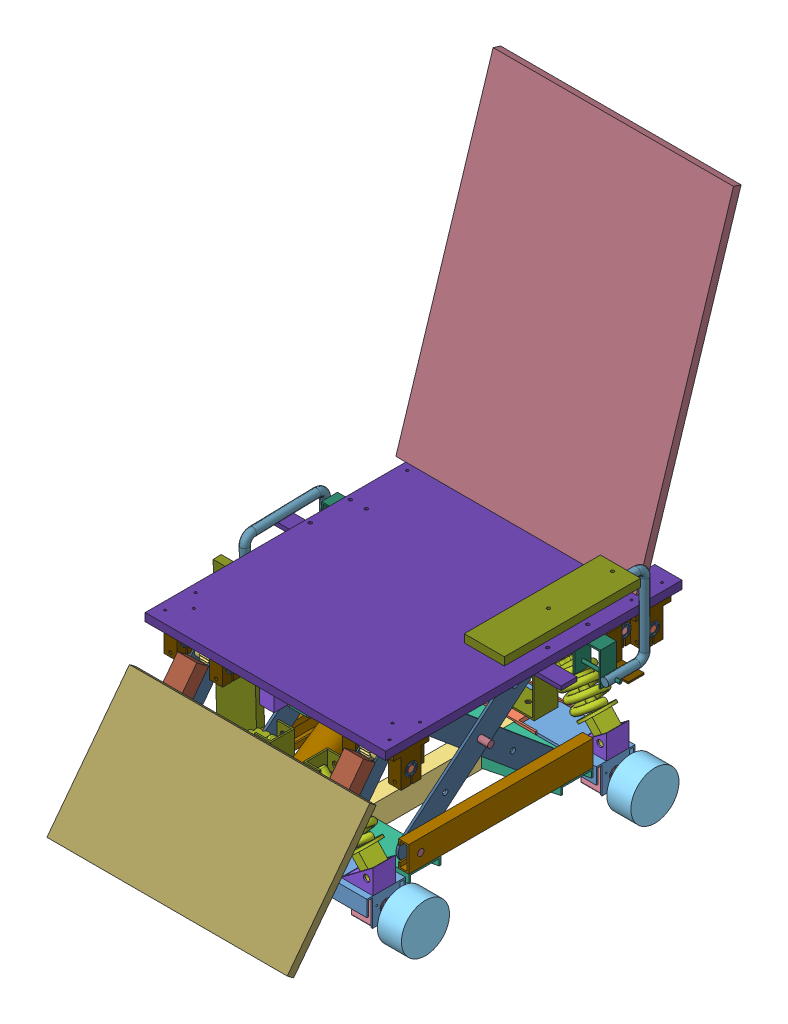
SolidWorks assembly 下半部, configuration 默认. Lengths in mm.
Overall size (394.98 643.7 566.47).
137 component instances, 36 part files, 107 mates.
Components (placement in the parent):
- 电机安装板-1: 电机安装板 [默认] at (86.7266 -11.8451 70) size (94 35 48)
- 电机转动副-1: 电机转动副 [默认] at (82.9126 -31.7003 67.7925) size (70 22 52)
- 矩管-1: 矩管 [默认] at (70.1397 -10.4653 43.5249) x (0 0 -1) z (0 1 0) size (338 20 30)
- 电机和减速器-1: 电机和减速器 [默认] at (33.1161 1.0347 94) x (0 0 1) z (-1 0 0) size (33 33 95)
- 轮子加法兰-1: 轮子加法兰 [默认] at (-93.8839 -6.7848 84.7644) x (0 0.763194 -0.646169) z (1 0 0) size (60 60 47)
- 升降支撑板-1: 升降支撑板 [默认] at (17.4717 0.0393 25.7925) size (99 30 40)
- 减震器10cm中心距-1: 减震器10cm中心距 [默认] at (-6.3734 50.215 84.5) x (0.68369 0.729773 0) z (0 0 1) size (112 51.88 51.88)
- 减震器安装支架-1: 减震器安装支架 [默认] at (-18.6767 23.9575 82.5) size (40 30 28)
- 导轨-1: 导轨 [默认] at (-3.9885 11.2083 65.7925) x (-1 0 0) z (0 0 -1) size (13 32 230)
- 升降剪叉机构-1: 升降剪叉机构 [默认] at (-28.8839 71.3664 -103.1847) x (0 0.642238 0.766505) z (1 0 0) size (258 30 3)
- 轴承带丝杆-1: 轴承带丝杆 [默认] at (-42.8839 24.6479 -118.7691) x (0 -0.824839 -0.565367) z (1 0 0) size (28 28 21)
- 升降剪叉机构-3: 升降剪叉机构 [默认] at (-31.8839 50.9021 12.8599) x (0 0.642238 -0.766505) z (1 0 0) size (258 30 3)
- 轴承带丝杆-2: 轴承带丝杆 [默认] at (-42.8839 173.169 -132.4789) x (0 0.15708 -0.987586) z (1 0 0) size (28 28 21)
- 减震器10cm中心距-2: 减震器10cm中心距 [默认] at (134.6055 50.215 108.5) x (-0.68369 0.729773 0) z (0 0 -1) size (112 51.88 51.88)
- 电机安装板-2: 电机安装板 [默认] at (41.5056 -11.8451 118) x (-1 0 0) z (0 0 -1) size (94 35 48)
- 减震器安装支架-2: 减震器安装支架 [默认] at (146.9089 23.9575 110.5) x (-1 0 0) z (0 0 -1) size (40 30 28)
- 轮子加法兰-2: 轮子加法兰 [默认] at (222.1161 -6.7848 84.7644) x (0 -0.763194 0.646169) z (-1 0 0) size (60 60 47)
- 电机和减速器-2: 电机和减速器 [默认] at (95.1161 1.0347 94) x (0 0 -1) z (1 0 0) size (33 33 95)
- 升降支撑板-2: 升降支撑板 [默认] at (110.7605 0.0393 65.7925) x (-1 0 0) z (0 0 -1) size (99 30 40)
- 升降剪叉机构-6: 升降剪叉机构 [默认] at (157.1161 50.9021 -86.038) x (0 0.642238 0.766505) z (-1 0 0) size (258 30 3)
- 升降剪叉机构-7: 升降剪叉机构 [默认] at (160.1161 71.3664 30.0065) x (0 0.642238 -0.766505) z (-1 0 0) size (258 30 3)
- 轴承带丝杆-5: 轴承带丝杆 [默认] at (171.1161 35.9711 -111.0078) x (0 0.824839 0.565367) z (-1 0 0) size (28 28 21)
- 导轨-7: 导轨 [默认] at (132.2207 61.8611 65.7925) x (1 0 0) z (0 0 -1) size (13 32 230)
- 导轨-8: 导轨 [默认] at (-3.9885 157.6386 65.7925) x (-1 0 0) z (0 0 -1) size (13 32 230)
- 轴承带丝杆-6: 轴承带丝杆 [默认] at (171.1161 171.0127 -118.9215) x (0 -0.15708 0.987586) z (-1 0 0) size (28 28 21)
- 导轨-11: 导轨 [默认] at (132.2207 208.2914 65.7925) x (1 0 0) z (0 0 -1) size (13 32 230)
- 轮子加法兰-3: 轮子加法兰 [默认] at (-93.8839 -6.7848 -183.1793) x (0 -0.763194 -0.646169) z (1 0 0) size (60 60 47)
- 减震器10cm中心距-3: 减震器10cm中心距 [默认] at (-6.3734 50.215 -206.9149) x (0.68369 0.729773 0) z (0 0 1) size (112 51.88 51.88)
- 电机安装板-3: 电机安装板 [默认] at (86.7266 -11.8451 -216.4149) size (94 35 48)
- 电机和减速器-3: 电机和减速器 [默认] at (33.1161 1.0347 -192.4149) x (0 0 1) z (-1 0 0) size (33 33 95)
- 减震器安装支架-3: 减震器安装支架 [默认] at (-18.6767 23.9575 -208.9149) size (40 30 28)
- 电机安装板-4: 电机安装板 [默认] at (41.5056 -11.8451 -168.4149) x (-1 0 0) z (0 0 -1) size (94 35 48)
- 减震器10cm中心距-4: 减震器10cm中心距 [默认] at (134.6055 50.215 -182.9149) x (-0.68369 0.729773 0) z (0 0 -1) size (112 51.88 51.88)
- 减震器安装支架-4: 减震器安装支架 [默认] at (146.9089 23.9575 -180.9149) x (-1 0 0) z (0 0 -1) size (40 30 28)
- 电机和减速器-4: 电机和减速器 [默认] at (95.1161 1.0347 -192.4149) x (0 0 -1) z (1 0 0) size (33 33 95)
- 轮子加法兰-4: 轮子加法兰 [默认] at (222.1161 -6.7848 -183.1793) x (0 0.763194 0.646169) z (-1 0 0) size (60 60 47)
- 电机转动副-2: 电机转动副 [默认] at (45.3195 -31.7003 -166.2075) x (-1 0 0) z (0 0 -1) size (70 22 52)
- 升降支撑板-3: 升降支撑板 [默认] at (17.4717 0.0393 -164.2075) size (99 30 40)
- 升降支撑板-4: 升降支撑板 [默认] at (110.7605 0.0393 -124.2075) x (-1 0 0) z (0 0 -1) size (99 30 40)
- M8 25-1: M8 25 [默认] at (-19.8839 182.965 50.7925) x (0 -0.872194 0.48916) z (-1 0 0) size (8 8 25)
- M820-1: M820 [默认] at (-24.8839 109.7499 -36.5891) x (0 0.001516 0.999999) z (-1 0 0) size (8 8 20)
- M820-2: M820 [默认] at (-24.8839 36.5347 50.7925) x (0 -0.155534 0.987831) z (-1 0 0) size (8 8 20)
- M820-3: M820 [默认] at (173.1161 36.5347 50.7925) x (0 -0.155534 0.987831) z (-1 0 0) size (8 8 20)
- M8 25-2: M8 25 [默认] at (173.1161 182.965 50.7925) x (0 -0.872194 0.48916) z (-1 0 0) size (8 8 25)
- M820-4: M820 [默认] at (173.1161 109.7499 -36.5891) x (0 0.001516 0.999999) z (-1 0 0) size (8 8 20)
- 推杆安装支架-1: 推杆安装支架 [默认] at (43.6161 55.5451 52.5195) x (0 0 -1) z (1 0 0) size (31 34.5 41)
- 推杆头-1: 推杆头 [默认] at (64.4401 95.7826 -5.2303) x (1 0 0) z (0 0.829277 0.558838) size (20 100 20)
- 减震器安装架-3: 减震器安装架 [默认] at (50.8491 12.0691 -177.2075) x (0 0 -1) z (1 0 0) size (30 98.12 81)
- 减震器安装架-4: 减震器安装架 [默认] at (77.383 12.0691 78.7925) x (0 0 1) z (-1 0 0) size (30 98.12 81)
- 装配体1-1: 装配体1 [默认] at (53.789 573.965 -39.11) x (-1 0 0) z (0 -1 0) size (300 370 54)
  - 坐垫-1: 坐垫 [默认] at (-124.3252 -195.4572 365) size (300 370 10)
  - 光轴支架-1: 光轴支架 [默认] at (-142.3271 -143.8242 371.8767) x (0 -1 0) z (-1 0 0) size (44 44 16)
  - deep groove ball bearings gb-1: deep groove ball bearings gb [Rolling bearings 618-8 GB 276-94] at (-145.2035 -140.9025 402) x (-1 0 0) z (0 -0.927196 -0.374576) size (4 16 16)
  - am8-1: am8 [默认] at (-86.5971 -156.6197 405.6451) x (0 -0.279688 0.960091) z (-1 0 0) size (8 8 71.73)
  - spur gear_gb-1: spur gear_gb [GB - Spur gear 1M 20T 20PA 12FW ---S20B75H20L8.0N] at (-116.3271 -140.9025 402) x (1 0 0) z (0 0.809131 -0.587628) size (20 21.8 21.8)
  - 光轴支架-2: 光轴支架 [默认] at (-142.3271 -118.2309 371.8767) x (0 1 0) z (1 0 0) size (44 44 16)
  - deep groove ball bearings gb-2: deep groove ball bearings gb [Rolling bearings 618-8 GB 276-94] at (-129.0651 -121.1525 402) size (4 16 16)
  - M8光轴连接齿轮-1: M8光轴连接齿轮 [默认] at (-142.3271 -136.3515 404.7888) x (0 0 -1) z (1 0 0) size (8 8 104.25)
  - deep groove ball bearings gb-3: deep groove ball bearings gb [Rolling bearings 618-8 GB 276-94] at (-140.8939 -121.1525 402) size (4 16 16)
  - deep groove ball bearings gb-4: deep groove ball bearings gb [Rolling bearings 618-8 GB 276-94] at (-156.497 -140.9025 402) x (-1 0 0) z (0 -0.924225 -0.381849) size (4 16 16)
  - 联轴器-1: 联轴器 [默认] at (-26.0771 -121.1525 402) x (0 0.642544 -0.766249) z (-1 0 0) size (14 14 20)
  - 双输出涡轮蜗杆电机-1: 双输出涡轮蜗杆电机 [默认] at (-27.3331 -113.7996 418) x (0 1 0) z (0 0 -1) size (76.8 52.5 32)
  - 零件1-1: 零件1 [默认] at (-21.0771 -118.3588 384) x (0 -1 0) z (-1 0 0) size (46 34 32)
  - spur gear_gb-5: spur gear_gb [GB - Spur gear 1M 20T 20PA 12FW ---S20B75H20L8.0N] at (-116.3271 -121.1525 402) x (1 0 0) z (0 -0.733673 0.679503) size (20 21.8 21.8)
  - 光轴支架-3: 光轴支架 [默认] at (-85.2921 -143.8242 371.8767) x (0 -1 0) z (-1 0 0) size (44 44 16)
  - deep groove ball bearings gb-7: deep groove ball bearings gb [Rolling bearings 618-8 GB 276-94] at (-87.2921 -140.9025 402) x (-1 0 0) z (0 -0.924225 -0.381849) size (4 16 16)
  - deep groove ball bearings gb-8: deep groove ball bearings gb [Rolling bearings 618-8 GB 276-94] at (-99.2921 -140.9025 402) size (4 16 16)
  - 光轴支架-4: 光轴支架 [默认] at (137.6729 -143.8242 371.8767) x (0 -1 0) z (-1 0 0) size (44 44 16)
  - deep groove ball bearings gb-9: deep groove ball bearings gb [Rolling bearings 618-8 GB 276-94] at (124.5493 -140.9025 402) x (1 0 0) z (0 0.927196 0.374576) size (4 16 16)
  - deep groove ball bearings gb-10: deep groove ball bearings gb [Rolling bearings 618-8 GB 276-94] at (120.2398 -121.1525 402) x (-1 0 0) z (0 0 -1) size (4 16 16)
  - am8-2: am8 [默认] at (137.6729 -156.6197 405.6451) x (0 -0.279688 0.960091) z (-1 0 0) size (8 8 71.73)
  - spur gear_gb-2: spur gear_gb [GB - Spur gear 1M 20T 20PA 12FW ---S20B75H20L8.0N] at (95.6729 -140.9025 402) x (-1 0 0) z (0 -0.809131 0.587628) size (20 21.8 21.8)
  - 光轴支架-5: 光轴支架 [默认] at (105.6729 -118.2309 371.8767) x (0 1 0) z (1 0 0) size (44 44 16)
  - M8光轴连接齿轮-2: M8光轴连接齿轮 [默认] at (17.4229 -136.3515 404.7888) x (0 0 -1) z (1 0 0) size (8 8 104.25)
  - deep groove ball bearings gb-11: deep groove ball bearings gb [Rolling bearings 618-8 GB 276-94] at (108.411 -121.1525 402) x (-1 0 0) z (0 0 -1) size (4 16 16)
  - deep groove ball bearings gb-12: deep groove ball bearings gb [Rolling bearings 618-8 GB 276-94] at (135.8428 -140.9025 402) x (1 0 0) z (0 0.924225 0.381849) size (4 16 16)
  - spur gear_gb-6: spur gear_gb [GB - Spur gear 1M 20T 20PA 12FW ---S20B75H20L8.0N] at (95.6729 -121.1525 402) x (-1 0 0) z (0 0.733673 -0.679503) size (20 21.8 21.8)
  - deep groove ball bearings gb-13: deep groove ball bearings gb [Rolling bearings 618-8 GB 276-94] at (66.6379 -140.9025 402) x (1 0 0) z (0 0.924225 0.381849) size (4 16 16)
  - 光轴支架-6: 光轴支架 [默认] at (80.6379 -143.8242 371.8767) x (0 -1 0) z (-1 0 0) size (44 44 16)
  - deep groove ball bearings gb-14: deep groove ball bearings gb [Rolling bearings 618-8 GB 276-94] at (78.6379 -140.9025 402) x (-1 0 0) z (0 0 -1) size (4 16 16)
  - 零件1-2: 零件1 [默认] at (0.4229 -103.9462 384) x (0 1 0) z (1 0 0) size (46 34 32)
  - 联轴器-2: 联轴器 [默认] at (5.4229 -121.1525 402) x (0 -0.642544 0.766249) z (1 0 0) size (14 14 20)
  - 光轴支架-13: 光轴支架 [默认] at (-158.3271 164.0191 371.8767) x (0 1 0) z (1 0 0) size (44 44 16)
  - deep groove ball bearings gb-27: deep groove ball bearings gb [Rolling bearings 618-8 GB 276-94] at (-156.497 161.0975 402) x (-1 0 0) z (0 -0.924225 0.381849) size (4 16 16)
  - deep groove ball bearings gb-28: deep groove ball bearings gb [Rolling bearings 618-8 GB 276-94] at (-145.2035 161.0975 402) x (-1 0 0) z (0 -0.927196 0.374576) size (4 16 16)
  - am8-5: am8 [默认] at (-158.3271 176.8147 405.6451) x (0 0.279688 0.960091) z (1 0 0) size (8 8 71.73)
  - 光轴支架-14: 光轴支架 [默认] at (-126.3271 138.4258 371.8767) x (0 -1 0) z (-1 0 0) size (44 44 16)
  - deep groove ball bearings gb-29: deep groove ball bearings gb [Rolling bearings 618-8 GB 276-94] at (-140.8939 141.3475 402) x (1 0 0) z (0 0 -1) size (4 16 16)
  - deep groove ball bearings gb-30: deep groove ball bearings gb [Rolling bearings 618-8 GB 276-94] at (-129.0651 141.3475 402) x (1 0 0) z (0 0 -1) size (4 16 16)
  - spur gear_gb-9: spur gear_gb [GB - Spur gear 1M 20T 20PA 12FW ---S20B75H20L8.0N] at (-116.3271 141.3475 402) x (1 0 0) z (0 -0.733673 -0.679503) size (20 21.8 21.8)
  - M8光轴连接齿轮-5: M8光轴连接齿轮 [默认] at (-38.0771 156.5465 404.7888) x (0 0 -1) z (-1 0 0) size (8 8 104.25)
  - spur gear_gb-10: spur gear_gb [GB - Spur gear 1M 20T 20PA 12FW ---S20B75H20L8.0N] at (-116.3271 161.0975 402) x (1 0 0) z (0 0.809131 0.587628) size (20 21.8 21.8)
  - 光轴支架-15: 光轴支架 [默认] at (-101.2921 164.0191 371.8767) x (0 1 0) z (1 0 0) size (44 44 16)
  - deep groove ball bearings gb-31: deep groove ball bearings gb [Rolling bearings 618-8 GB 276-94] at (-99.2921 161.0975 402) x (1 0 0) z (0 0 -1) size (4 16 16)
  - deep groove ball bearings gb-32: deep groove ball bearings gb [Rolling bearings 618-8 GB 276-94] at (-87.2921 161.0975 402) x (-1 0 0) z (0 -0.924225 0.381849) size (4 16 16)
  - 零件1-5: 零件1 [默认] at (-21.0771 124.1412 384) x (0 -1 0) z (-1 0 0) size (46 34 32)
  - 联轴器-5: 联轴器 [默认] at (-26.0771 141.3475 402) x (0 0.642544 0.766249) z (-1 0 0) size (14 14 20)
  - 零件1-6: 零件1 [默认] at (0.4229 138.5538 384) x (0 1 0) z (1 0 0) size (46 34 32)
  - 联轴器-6: 联轴器 [默认] at (5.4229 141.3475 402) x (0 -0.642544 -0.766249) z (1 0 0) size (14 14 20)
  - M8光轴连接齿轮-6: M8光轴连接齿轮 [默认] at (121.6729 156.5465 404.7888) x (0 0 -1) z (-1 0 0) size (8 8 104.25)
  - 光轴支架-16: 光轴支架 [默认] at (121.6729 138.4258 371.8767) x (0 -1 0) z (-1 0 0) size (44 44 16)
  - spur gear_gb-11: spur gear_gb [GB - Spur gear 1M 20T 20PA 12FW ---S20B75H20L8.0N] at (95.6729 141.3475 402) x (-1 0 0) z (0 0.733673 0.679503) size (20 21.8 21.8)
  - deep groove ball bearings gb-33: deep groove ball bearings gb [Rolling bearings 618-8 GB 276-94] at (108.411 141.3475 402) x (-1 0 0) z (0 0 1) size (4 16 16)
  - deep groove ball bearings gb-34: deep groove ball bearings gb [Rolling bearings 618-8 GB 276-94] at (120.2398 141.3475 402) x (-1 0 0) z (0 0 1) size (4 16 16)
  - am8-6: am8 [默认] at (65.9429 176.8147 405.6451) x (0 0.279688 0.960091) z (1 0 0) size (8 8 71.73)
  - 光轴支架-17: 光轴支架 [默认] at (121.6729 164.0191 371.8767) x (0 1 0) z (1 0 0) size (44 44 16)
  - 光轴支架-18: 光轴支架 [默认] at (64.6379 164.0191 371.8767) x (0 1 0) z (1 0 0) size (44 44 16)
  - spur gear_gb-12: spur gear_gb [GB - Spur gear 1M 20T 20PA 12FW ---S20B75H20L8.0N] at (95.6729 161.0975 402) x (-1 0 0) z (0 -0.809131 -0.587628) size (20 21.8 21.8)
  - deep groove ball bearings gb-35: deep groove ball bearings gb [Rolling bearings 618-8 GB 276-94] at (78.6379 161.0975 402) x (-1 0 0) z (0 0 1) size (4 16 16)
  - deep groove ball bearings gb-36: deep groove ball bearings gb [Rolling bearings 618-8 GB 276-94] at (66.6379 161.0975 402) x (1 0 0) z (0 0.924225 -0.381849) size (4 16 16)
  - 双输出涡轮蜗杆电机-3: 双输出涡轮蜗杆电机 [默认] at (-27.3331 133.9946 386) x (0 -1 0) z (0 0 1) size (76.8 52.5 32)
  - deep groove ball bearings gb-37: deep groove ball bearings gb [Rolling bearings 618-8 GB 276-94] at (135.8428 161.0975 402) x (1 0 0) z (0 0.924225 -0.381849) size (4 16 16)
  - 接近开关-1: 接近开关 [默认] at (-3.0771 -170.4461 383.327) x (0 -1 0) z (-1 0 0) size (36 18 18)
  - 接近开关-2: 接近开关 [默认] at (-21.0771 190.6411 383.327) x (0 1 0) z (1 0 0) size (36 18 18)
- 105mm推杆-1: 105mm推杆 [默认] at (74.1161 80.96 110.6424) x (0 0.558838 -0.829277) z (-1 0 0) size (114.5 80 40.32)
- 接近开关-1: 接近开关 [默认] at (10.3316 204.5086 -208.2075) x (0 1 0) z (0 0 1) size (36 18 18)
- 接近开关-3: 接近开关 [默认] at (104.6161 27.8617 113.5436) x (0 0 1) z (-1 0 0) size (36 18 18)
- 零件6-1: 零件6 [默认] at (-29.884 177.4429 -202.1316) x (0 0.952867 -0.303388) z (1 0 0) size (87 17 24)
- 零件7-1: 零件7 [默认] at (-27.884 248.7847 -215.7461) x (0 0.952867 -0.303388) z (0 0.303388 0.952867) size (70 24 18.5)
- 零件6-2: 零件6 [默认] at (178.1161 177.4429 -202.1316) x (0 0.952867 -0.303388) z (1 0 0) size (87 17 24)
- 零件7-2: 零件7 [默认] at (156.1161 254.3974 -198.118) x (0 0.952867 -0.303388) z (0 -0.303388 -0.952867) size (70 24 18.5)
- 零件6-3: 零件6 [默认] at (-49.884 167.2448 105.1733) x (0 -0.795425 0.606052) z (-1 0 0) size (87 17 24)
- 零件6-4: 零件6 [默认] at (158.1161 167.2448 105.1733) x (0 -0.795425 0.606052) z (-1 0 0) size (87 17 24)
- 下-1: 下 [默认] at (190.3789 111.5042 181.8031) x (0 -0.795425 0.606052) z (0 0.606052 0.795425) size (170 300 10)
- 零件7-7: 零件7 [默认] at (180.1161 143.6396 134.0604) x (0 0.795425 -0.606052) z (0 0.606052 0.795425) size (70 24 18.5)
- 零件7-8: 零件7 [默认] at (-27.884 143.6396 134.0604) x (0 0.795425 -0.606052) z (0 0.606052 0.795425) size (70 24 18.5)
- 上-1: 上 [默认] at (-62.1467 272.1868 -203.7821) x (0 0.952867 -0.303388) z (0 0.303388 0.952867) size (400 300 10)
- 零件2-1: 零件2 [默认] at (-110.8839 156.9682 -114.4611) x (0 -0.999678 -0.025364) z (-1 0 0) size (155 110 10)
- 零件3-1: 零件3 [默认] at (-66.9203 168.1196 -124.2075) size (50 42 20)
- 手柄-1: 手柄 [默认] at (-106.1112 133.7841 -10.0155) x (1 0 0) z (0 -0.025364 0.999678) size (50 170 10)
- 零件4-2: 零件4 [默认] at (-85.5832 193.965 -51.5963) x (1 0 0) z (0 1 0) size (40 20 5)
- 零件3-2: 零件3 [默认] at (190.1307 168.1196 -117.4608) x (-1 0 0) z (0 0 -1) size (50 42 20)
- 零件4-5: 零件4 [默认] at (213.8154 198.965 -51.5963) x (-1 0 0) z (0 -1 0) size (40 20 5)
- 手柄-2: 手柄 [默认] at (229.3217 281.965 -96.9332) x (-1 0 0) z (0 -1 0) size (50 170 10)
- 零件2-4: 零件2 [默认] at (234.0944 166.965 -117.4608) x (0 0 1) z (-1 0 0) size (155 110 10)
- 零件5-1: 零件5 [默认] at (196.508 162.6047 -137.4608) x (-1 0 0) z (0 0 -1) size (50 39 20)
- 零件5-2: 零件5 [默认] at (-68.2759 162.6047 -157.4608) size (50 39 20)
Mates (geometry in assembly coordinates):
- 同心1: concentric: cylinder of 电机安装板-1 through (39.1161 9.5347 118) axis (0 0 -1) radius 4; cylinder of 电机转动副-1 through (39.1161 9.5347 119.7925) axis (0 0 -1) radius 4
- 重合1: coincident: plane of 电机安装板-1 through (86.7266 -11.8451 118) normal (0 0 1); plane of 电机转动副-1 through (52.1161 -22.4653 118) normal (0 0 -1)
- 同心2: concentric: cylinder of 电机转动副-1 through (64.1161 -22.4653 93.7925) axis (0 1 0) radius 4; cylinder of 矩管-1 through (64.1161 19.5347 93.7925) axis (0 -1 0) radius 4
- 重合2: coincident: plane of 电机转动副-1 through (54.1161 19.5347 119.7925) normal (0 -1 0); plane of 矩管-1 through (70.1397 19.5347 43.5249) normal (0 1 0)
- 同心3: concentric: cylinder of 电机安装板-1 through (-42.8839 1.0347 94) axis (-1 0 0) radius 7.5; cylinder of 电机和减速器-1 through (-43.8839 1.0347 94) axis (1 0 0) radius 5
- 重合3: coincident: plane of 电机安装板-1 through (-42.8839 -11.8451 70) normal (1 0 0); plane of 电机和减速器-1 through (-42.8839 15.5347 79.5) normal (-1 0 0)
- 重合4: coincident: plane of 电机和减速器-1 through (-61.8839 1.0347 94) normal (-1 0 0); plane of 轮子加法兰-1 through (-61.8839 1.0347 94) normal (1 0 0)
- 同心4: concentric: cylinder of 电机和减速器-1 through (-61.8839 1.0347 94) axis (1 0 0) radius 3; cylinder of 轮子加法兰-1 through (-61.8839 1.0347 94) axis (1 0 0) radius 3
- 重合9: coincident: circle of 矩管-1; cylinder of 升降支撑板-1 through (149.1161 4.5347 45.7925) axis (-1 0 0) radius 4
- 重合10: coincident: plane of 矩管-1 through (54.1161 19.5347 119.7925) normal (-1 0 0); plane of 升降支撑板-1 through (54.1161 20.5347 65.7925) normal (1 0 0)
- 重合11: coincident: plane of 电机和减速器-1 through (-42.8839 -13.4653 110.5) normal (0 0 1); plane of 减震器安装支架-1 through (-18.6767 23.9575 110.5) normal (0 0 1)
- 重合12: coincident: plane of 电机安装板-1 through (-44.8839 19.5347 118) normal (0 1 0); plane of 减震器安装支架-1 through (-44.8839 19.5347 110.5) normal (0 -1 0)
- 重合13: coincident: plane of 电机安装板-1 through (-44.8839 -0.4653 118) normal (-1 0 0); plane of 减震器安装支架-1 through (-44.8839 49.5347 110.5) normal (-1 0 0)
- 同心6: concentric: cylinder of 减震器10cm中心距-1 through (-36.8839 34.5347 108.5) axis (0 0 -1) radius 4; cylinder of 减震器安装支架-1 through (-36.8839 34.5347 110.5) axis (0 0 -1) radius 4
- 重合14: coincident: plane of 减震器10cm中心距-1 through (-36.8839 34.5347 108.5) normal (0 0 1); plane of 减震器安装支架-1 through (-42.8839 21.5347 108.5) normal (0 0 -1)
- 同心10: concentric: cylinder of 升降剪叉机构-1 through (-25.8839 36.5347 -123.9706) axis (-1 0 0) radius 4; cylinder of 轴承带丝杆-1 through (-21.8839 36.5347 -123.9706) axis (-1 0 0) radius 4
- 重合15: coincident: plane of 升降支撑板-1 through (-44.8839 20.5347 65.7925) normal (0 1 0); plane of 导轨-1 through (-31.8839 20.5347 -164.2075) normal (0 -1 0)
- 重合16: coincident: line of 升降支撑板-1 through (-44.8839 20.5347 25.7925) axis (0 -1 0); plane of 导轨-1 through (-44.8839 20.5347 -164.2075) normal (-1 0 0)
- 重合17: coincident: plane of 升降支撑板-1 through (17.4717 0.0393 65.7925) normal (0 0 1); plane of 导轨-1 through (-3.9885 11.2083 65.7925) normal (0 0 1)
- 相切1: tangent: plane of 导轨-1 through (-33.8839 50.5347 -164.2075) normal (0 -1 0); cylinder of 轴承带丝杆-1 through (-33.8839 36.5347 -123.9706) axis (-1 0 0) radius 14
- 重合20: coincident: circle of 升降剪叉机构-1; plane of 升降剪叉机构-3 through (-28.8839 36.5347 50.7925) normal (1 0 0)
- 重合21: coincident: plane of 导轨-1 through (-31.8839 50.5347 -164.2075) normal (1 0 0); plane of 升降剪叉机构-3 through (-31.8839 36.5347 50.7925) normal (-1 0 0)
- 同心12: concentric: cylinder of 升降剪叉机构-1 through (-25.8839 109.7499 -36.5891) axis (-1 0 0) radius 4; cylinder of 升降剪叉机构-3 through (-28.8839 109.7499 -36.5891) axis (-1 0 0) radius 4
- 同心13: concentric: cylinder of 升降剪叉机构-3 through (-28.8839 182.965 -123.9706) axis (-1 0 0) radius 4; cylinder of 轴承带丝杆-2 through (-21.8839 182.965 -123.9706) axis (-1 0 0) radius 4
- 重合33: coincident: plane of 升降支撑板-2 through (173.1161 20.5347 25.7925) normal (0 1 0); plane of 导轨-7 through (173.1161 20.5347 -164.2075) normal (0 -1 0)
- 同心17: concentric: cylinder of 升降剪叉机构-7 through (157.1161 36.5347 50.7925) axis (1 0 0) radius 4; cylinder of 导轨-7 through (161.1161 36.5347 50.7925) axis (1 0 0) radius 4
- 重合34: coincident: plane of 导轨-1 through (-3.9885 11.2083 65.7925) normal (0 0 1); line of 导轨-7 through (171.1161 22.5347 65.7925) axis (0 1 0)
- 重合35: coincident: plane of 升降支撑板-2 through (173.1161 20.5347 25.7925) normal (1 0 0); plane of 导轨-7 through (173.1161 52.5347 -164.2075) normal (1 0 0)
- 同心18: concentric: cylinder of 升降剪叉机构-1 through (-25.8839 182.965 50.7925) axis (-1 0 0) radius 4; cylinder of 导轨-8 through (-32.8839 182.965 50.7925) axis (-1 0 0) radius 4
- 重合36: coincident: plane of 导轨-1 through (-44.8839 20.5347 -164.2075) normal (-1 0 0); plane of 导轨-8 through (-44.8839 166.965 -164.2075) normal (-1 0 0)
- 重合38: coincident: plane of 导轨-7 through (173.1161 52.5347 -164.2075) normal (1 0 0); plane of 导轨-11 through (173.1161 198.965 -164.2075) normal (1 0 0)
- 同心19: concentric: cylinder of 升降剪叉机构-1 through (-25.8839 109.7499 -36.5891) axis (-1 0 0) radius 4; cylinder of M820-1 through (-44.8839 109.7499 -36.5891) axis (1 0 0) radius 4
- 同心20: concentric: cylinder of 升降剪叉机构-1 through (-25.8839 182.965 50.7925) axis (-1 0 0) radius 4; cylinder of M8 25-1 through (-44.8839 182.965 50.7925) axis (1 0 0) radius 4
- 重合41: coincident: plane of 导轨-8 through (-44.8839 166.965 -164.2075) normal (-1 0 0); plane of M820-1 through (-44.8839 109.7499 -36.5891) normal (-1 0 0)
- 重合42: coincident: plane of 导轨-8 through (-44.8839 166.965 -164.2075) normal (-1 0 0); plane of M8 25-1 through (-44.8839 182.965 50.7925) normal (-1 0 0)
- 重合43: coincident: plane of 导轨-1 through (-44.8839 20.5347 -164.2075) normal (-1 0 0); plane of M820-2 through (-44.8839 36.5347 50.7925) normal (-1 0 0)
- 同心21: concentric: cylinder of 导轨-1 through (-32.8839 36.5347 50.7925) axis (-1 0 0) radius 4; cylinder of M820-2 through (-44.8839 36.5347 50.7925) axis (1 0 0) radius 4
- 同心22: concentric: cylinder of 导轨-11 through (161.1161 182.965 50.7925) axis (1 0 0) radius 4; cylinder of M8 25-2 through (148.1161 182.965 50.7925) axis (1 0 0) radius 4
- 重合46: coincident: plane of 轴承带丝杆-5 through (171.1161 36.5347 -123.9706) normal (1 0 0); plane of 导轨-7 through (171.1161 22.5347 -164.2075) normal (-1 0 0)
- 重合47: coincident: plane of 导轨-1 through (-42.8839 50.5347 -164.2075) normal (1 0 0); plane of 轴承带丝杆-1 through (-42.8839 36.5347 -123.9706) normal (-1 0 0)
- 重合50: coincident: plane of 轴承带丝杆-6 through (171.1161 182.965 -123.9706) normal (1 0 0); plane of 导轨-11 through (171.1161 168.965 -164.2075) normal (-1 0 0)
- 重合51: coincident: plane of 轴承带丝杆-2 through (-42.8839 182.965 -123.9706) normal (-1 0 0); plane of 导轨-8 through (-42.8839 196.965 -164.2075) normal (1 0 0)
- 重合57: coincident: plane of 矩管-1 through (74.1161 19.5347 119.7925) normal (1 0 0); plane of 电机转动副-2 through (74.1161 -0.4653 -218.2075) normal (-1 0 0)
- 平行1: parallel: plane of 电机安装板-4 through (173.1161 19.5347 -216.4149) normal (0 1 0); plane of 电机转动副-2 through (74.1161 21.5347 -218.2075) normal (0 1 0)
- 重合61: coincident: plane of 导轨-1 through (-31.8839 20.5347 -164.2075) normal (0 -1 0); plane of 升降支撑板-3 through (-44.8839 20.5347 -124.2075) normal (0 1 0)
- 重合62: coincident: plane of 导轨-7 through (173.1161 20.5347 -164.2075) normal (0 -1 0); plane of 升降支撑板-4 through (173.1161 20.5347 -164.2075) normal (0 1 0)
- 重合63: coincident: plane of 电机转动副-2 through (74.1161 21.5347 -218.2075) normal (0 1 0); plane of 减震器安装架-3 through (41.6161 21.5347 -207.2075) normal (0 -1 0)
- 平行2: parallel: plane of 导轨-1 through (-44.8839 52.5347 -164.2075) normal (0 1 0); plane of 导轨-8 through (-31.8839 166.965 -164.2075) normal (0 -1 0)
- 重合64: coincident: plane of 导轨-8 through (-44.8839 198.965 -164.2075) normal (0 1 0); plane of 装配体1-1/坐垫-1 through (178.1142 198.965 156.3472) normal (0 -1 0)
- 同心28: concentric: cylinder of 推杆安装支架-1 through (64.1161 -13.9653 93.7925) axis (0 1 0) radius 3; cylinder of 减震器安装架-4 through (64.1161 -70.5853 93.7925) axis (0 1 0) radius 3
- 同心29: concentric: cylinder of 电机转动副-1 through (64.1161 -22.4653 93.7925) axis (0 1 0) radius 4; cylinder of 减震器安装架-4 through (64.1161 -70.5853 93.7925) axis (0 1 0) radius 3
- 重合65: coincident: plane of 推杆安装支架-1 through (84.6161 23.5347 103.7925) normal (0 -1 0); plane of 减震器安装架-4 through (43.6161 23.5347 108.7925) normal (0 1 0)
- 同心30: concentric: cylinder of 推杆安装支架-1 through (84.6161 49.5347 81.2925) axis (-1 0 0) radius 5.25; cylinder of 105mm推杆-1 through (44.1161 49.5347 81.2925) axis (1 0 0) radius 4
- 同心31: concentric: cylinder of 推杆头-1 through (64.4401 151.6664 -88.158) axis (0 -0.558838 0.829277) radius 10; cylinder of 105mm推杆-1 through (64.4401 71.978 30.0939) axis (0 0.558838 -0.829277) radius 10
- 重合68: coincident: line of 105mm推杆-1 through (64.1161 62.3072 78.4439) axis (0 0.558838 -0.829277); plane of assembly
- 重合69: coincident: plane of 装配体1-1 through (64.1161 573.965 -39.11) normal (1 0 0); plane of assembly through (64.2634 1.0941 0) normal (0.999855 0.017023 0)
- 重合70: coincident: plane of 装配体1-1 through (53.789 573.965 -49.2075) normal (0 0 1); plane of assembly through (0 0 -49.2075) normal (0 0 1)
- 重合71: coincident: plane of 装配体1-1/坐垫-1 through (18.6587 208.965 -208.2075) normal (0 0 1); plane of 接近开关-1 through (10.3316 204.5086 -208.2075) normal (0 0 -1)
- 重合72: coincident: plane of 装配体1-1/坐垫-1 through (178.1142 208.965 156.3472) normal (0 1 0); plane of 接近开关-1 through (18.6587 208.965 -190.2075) normal (0 1 0)
- 重合73: coincident: plane of 装配体1-1/坐垫-1 through (18.6587 208.965 -199.2075) normal (-1 0 0); plane of 接近开关-1 through (18.6587 202.965 -190.2075) normal (1 0 0)
- 重合77: coincident: plane of 减震器安装架-4 through (86.6161 98.0253 108.7925) normal (1 0 0); plane of 接近开关-3 through (86.6161 27.8617 113.5436) normal (-1 0 0)
- 重合78: coincident: plane of 电机安装板-2 through (173.1161 19.5347 70) normal (0 1 0); plane of 接近开关-3 through (86.6161 19.5347 112) normal (0 -1 0)
- 重合79: coincident: plane of 电机转动副-1 through (76.1161 -22.4653 118) normal (0 0 -1); plane of 接近开关-3 through (86.6161 19.5347 118) normal (0 0 1)
- 同心32: concentric: circle of 升降剪叉机构-7; cylinder of 推杆头-1 through (164.4401 146.3574 -80.2798) axis (-1 0 0) radius 3.25
- 重合80: coincident: plane of 导轨-11 through (160.1161 198.965 -164.2075) normal (0 1 0); plane of 装配体1-1/坐垫-1 through (178.1142 198.965 156.3472) normal (0 -1 0)
- 同心33: concentric: cylinder of 装配体1-1/am8-6 through (-83.8839 171.965 -200.2075) axis (1 0 0) radius 4; cylinder of 零件6-1 through (-51.884 171.965 -200.2075) axis (1 0 0) radius 4
- 重合81: coincident: plane of 装配体1-1/spur gear_gb-12 through (-49.884 171.965 -200.2075) normal (-1 0 0); plane of 零件6-1 through (-49.884 173.3943 -200.6626) normal (1 0 0)
- 重合82: coincident: plane of 零件6-1 through (-27.884 175.9731 -192.5632) normal (0 0.303388 0.952867); plane of 零件7-1 through (-27.884 248.7847 -215.7461) normal (0 -0.303388 -0.952867)
- 重合83: coincident: plane of 零件6-1 through (-51.884 173.3943 -200.6626) normal (-1 0 0); plane of 零件7-1 through (-51.884 218.2712 -186.6156) normal (-1 0 0)
- 重合84: coincident: plane of 零件6-1 through (-49.884 212.6585 -204.2436) normal (0 -0.952867 0.303388); plane of 零件7-1 through (-27.884 218.2712 -186.6156) normal (0 -0.952867 0.303388)
- 同心34: concentric: cylinder of 装配体1-1/am8-2 through (-12.1539 171.965 101.7925) axis (-1 0 0) radius 4; cylinder of 零件6-3 through (-51.884 171.965 101.7925) axis (1 0 0) radius 4
- 重合88: coincident: plane of 装配体1-1/spur gear_gb-2 through (-49.884 171.965 101.7925) normal (-1 0 0); plane of 零件6-3 through (-49.884 170.7719 102.7016) normal (1 0 0)
- 同心35: concentric: cylinder of 装配体1-1/am8-1 through (212.1161 171.965 101.7925) axis (-1 0 0) radius 4; cylinder of 零件6-4 through (180.1161 171.965 101.7925) axis (-1 0 0) radius 4
- 重合89: coincident: plane of 装配体1-1/spur gear_gb-1 through (178.1161 171.965 101.7925) normal (1 0 0); plane of 零件6-4 through (178.1161 170.7719 102.7016) normal (-1 0 0)
- 重合96: coincident: plane of 装配体1-1/坐垫-1 through (-85.8839 198.965 -234.2075) normal (-1 0 0); plane of 下-1 through (-85.8839 162.5719 155.4653) normal (-1 0 0)
- 平行3: parallel: plane of 零件6-3 through (-51.884 175.9233 109.4627) normal (0 0.606052 0.795425); plane of 下-1 through (190.3789 111.5042 181.8031) normal (0 -0.606052 -0.795425)
- 重合100: coincident: plane of 零件6-3 through (-51.884 175.9233 109.4627) normal (0 0.606052 0.795425); plane of 零件7-8 through (-27.884 143.6396 134.0604) normal (0 -0.606052 -0.795425)
- 重合101: coincident: plane of 零件6-3 through (-51.884 170.7719 102.7016) normal (-1 0 0); plane of 零件7-8 through (-51.884 124.6944 171.7532) normal (-1 0 0)
- 重合102: coincident: plane of 零件6-3 through (-51.884 113.4825 157.0378) normal (0 -0.795425 0.606052); plane of 零件7-8 through (-27.884 124.6944 171.7532) normal (0 -0.795425 0.606052)
- 重合103: coincident: plane of 零件6-4 through (156.1161 175.9233 109.4627) normal (0 0.606052 0.795425); plane of 零件7-7 through (180.1161 143.6396 134.0604) normal (0 -0.606052 -0.795425)
- 重合104: coincident: plane of 零件6-4 through (156.1161 113.4825 157.0378) normal (0 -0.795425 0.606052); plane of 零件7-7 through (180.1161 124.6944 171.7532) normal (0 -0.795425 0.606052)
- 重合105: coincident: plane of 零件6-4 through (180.1161 170.7719 102.7016) normal (1 0 0); plane of 零件7-7 through (180.1161 180.3742 129.3295) normal (1 0 0)
- 重合107: coincident: plane of 下-1 through (190.3789 111.5042 181.8031) normal (0 -0.606052 -0.795425); plane of 零件7-8 through (-27.884 154.8515 148.7758) normal (0 0.606052 0.795425)
- 重合108: coincident: plane of 零件6-3 through (-29.884 145.2994 132.7957) normal (0 0.795425 -0.606052); plane of 下-1 through (214.1161 162.5719 155.4653) normal (0 0.795425 -0.606052)
- 重合109: coincident: plane of 下-1 through (190.3789 111.5042 181.8031) normal (0 -0.606052 -0.795425); plane of 零件7-7 through (180.1161 154.8515 148.7758) normal (0 0.606052 0.795425)
- 重合110: coincident: plane of 零件7-1 through (-27.884 218.2712 -186.6156) normal (0 -0.952867 0.303388); plane of 上-1 through (-85.8839 221.305 -177.0869) normal (0 -0.952867 0.303388)
- 重合111: coincident: plane of 零件7-1 through (-27.884 254.3974 -198.118) normal (0 0.303388 0.952867); plane of 上-1 through (-62.1467 272.1868 -203.7821) normal (0 -0.303388 -0.952867)
- 重合112: coincident: plane of 装配体1-1/坐垫-1 through (-85.8839 198.965 -234.2075) normal (-1 0 0); plane of 上-1 through (-85.8839 602.4519 -298.4422) normal (-1 0 0)
- 重合113: coincident: plane of 装配体1-1/坐垫-1 through (178.1142 198.965 156.3472) normal (0 -1 0); plane of 零件3-1 through (-71.8839 198.965 -104.2075) normal (0 1 0)
- 相切2: tangent: cylinder of 零件2-1 through (-110.8839 156.9682 -114.4611) axis (0 0.999678 0.025364) radius 5; plane of 零件3-1 through (-105.8839 196.965 -104.2075) normal (-1 0 0)
- 同心37: concentric: cylinder of 零件2-1 through (-110.8839 161.9177 84.7285) axis (0 0.025364 -0.999678) radius 2; cylinder of 手柄-1 through (-110.8839 164.0482 0.7555) axis (0 0.025364 -0.999678) radius 2
- 同心38: concentric: cylinder of 零件2-1 through (-110.8839 81.9434 82.6994) axis (0 0.025364 -0.999678) radius 2; cylinder of 手柄-1 through (-110.8839 84.0739 -1.2735) axis (0 0.025364 -0.999678) radius 2
- 相切3: tangent: cylinder of 零件2-1 through (-110.8839 194.419 -13.4787) axis (0 -0.999678 -0.025364) radius 5; plane of 手柄-1 through (-106.1112 133.7841 -10.0155) normal (0 0.025364 -0.999678)
- 同心40: concentric: cylinder of 零件2-1 through (-120.8839 166.965 -114.2075) axis (1 0 0) radius 2; cylinder of 零件3-1 through (-70.8839 166.965 -114.2075) axis (-1 0 0) radius 2
- 同心42: concentric: cylinder of 装配体1-1/坐垫-1 through (-79.8839 208.965 -114.2075) axis (0 -1 0) radius 2; cylinder of 零件3-1 through (-79.8839 196.965 -114.2075) axis (0 1 0) radius 2
- 重合115: coincident: plane of 装配体1-1/坐垫-1 through (178.1142 198.965 156.3472) normal (0 -1 0); plane of 零件4-2 through (-85.5832 198.965 -51.5963) normal (0 1 0)
- 同心43: concentric: cylinder of 装配体1-1/坐垫-1 through (-79.8839 208.965 -64.2075) axis (0 -1 0) radius 2; cylinder of 零件4-2 through (-79.8839 198.965 -64.2075) axis (0 -1 0) radius 2
- 同心47: concentric: cylinder of 零件3-2 through (194.0944 166.965 -127.4608) axis (1 0 0) radius 2; cylinder of 零件2-4 through (224.0944 166.965 -127.4608) axis (1 0 0) radius 2
- 重合117: coincident: plane of 装配体1-1/坐垫-1 through (178.1142 198.965 156.3472) normal (0 -1 0); plane of 零件3-2 through (195.0944 198.965 -137.4608) normal (0 1 0)
- 相切6: tangent: plane of 零件3-2 through (229.0944 196.965 -137.4608) normal (1 0 0); cylinder of 零件2-4 through (234.0944 166.965 -117.4608) axis (0 0 -1) radius 5
- 同心48: concentric: cylinder of 装配体1-1/坐垫-1 through (203.0944 208.965 -127.4608) axis (0 -1 0) radius 2; cylinder of 零件3-2 through (203.0944 196.965 -127.4608) axis (0 1 0) radius 2
- 重合119: coincident: plane of 装配体1-1/坐垫-1 through (178.1142 198.965 156.3472) normal (0 -1 0); plane of 零件5-1 through (213.6836 198.965 -157.4608) normal (0 1 0)
- 重合120: coincident: plane of 零件3-2 through (190.1307 168.1196 -137.4608) normal (0 0 -1); plane of 零件5-1 through (196.508 162.6047 -137.4608) normal (0 0 1)
- 同心50: concentric: cylinder of 手柄-2 through (234.0944 271.965 -127.4608) axis (0 1 0) radius 2; cylinder of 零件2-4 through (234.0944 365.965 -127.4608) axis (0 -1 0) radius 2
- 同心51: concentric: cylinder of 手柄-2 through (234.0944 271.965 -47.4608) axis (0 1 0) radius 2; cylinder of 零件2-4 through (234.0944 365.965 -47.4608) axis (0 -1 0) radius 2
- 相切7: tangent: plane of 手柄-2 through (229.3217 271.965 -96.9332) normal (0 -1 0); cylinder of 零件2-4 through (234.0944 266.965 -157.4608) axis (0 0 1) radius 5
- 平行6: parallel: plane of 装配体1-1/坐垫-1 through (-85.8839 198.965 -234.2075) normal (-1 0 0); plane of 零件3-1 through (-105.8839 196.965 -104.2075) normal (-1 0 0)
